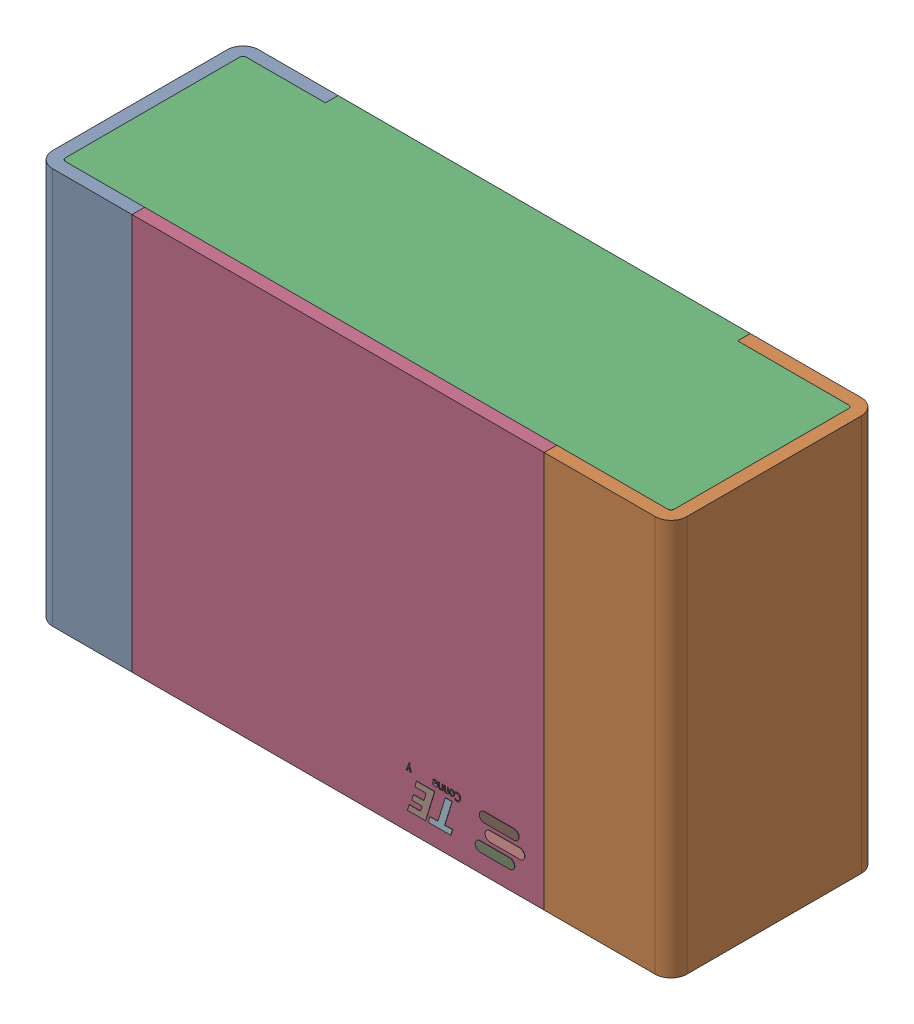
SolidWorks assembly R_MH4.step, configuration Default. Lengths in mm.
Overall size (2 1.25 0.65).
5 component instances, 4 part files, 0 mates.
Components (placement in the parent):
- Res_TE_Connectivity_CPF0805B66R5E1_eec.step-1: Res_TE_Connectivity_CPF0805B66R5E1_eec.step [Default] at (51.169 7.493 0) x (-1 0 0) z (0 0 1) size (2 1.25 0.65)
  - 1.step-1: 1.step [Default] at origin size (2 1.25 0.65)
  - 2.step-1: 2.step [Default] at origin size (1.92 1.25 0.61)
  - 3.step-1: 3.step [Default] at origin size (1.3 1.25 0.04)
  - TE connectivity Logo 1 (2).step-1: TE connectivity Logo 1 (2).step [Default] at (5.4285 0.313 0.551) x (-1 0 0) z (0 0 1) size (0.37 0.13 0.11)
